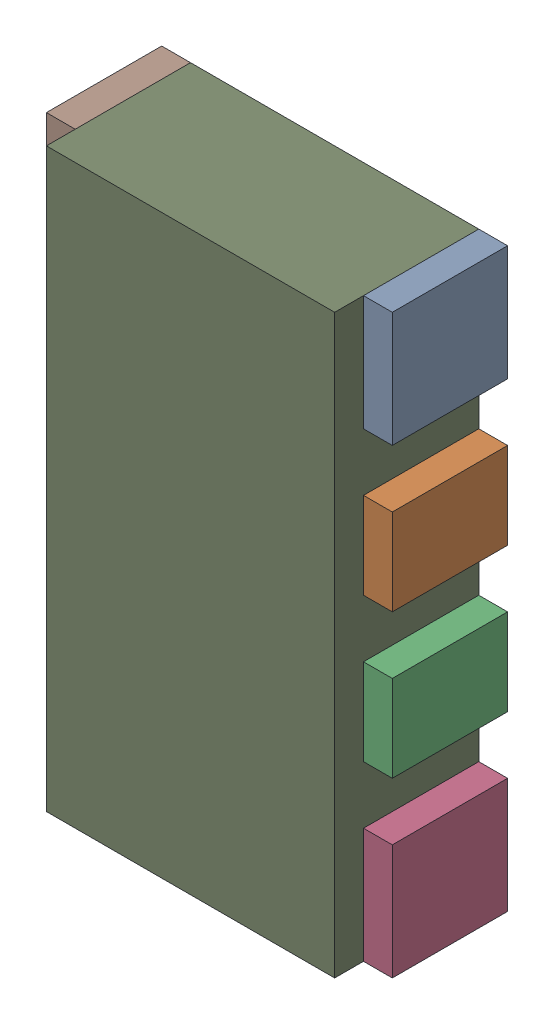
SolidWorks assembly RN4, configuration Default. Lengths in mm.
Overall size (1.2 2 0.5).
18 component instances, 3 part files, 0 mates.
Components (placement in the parent):
- 791587232-1: 791587232 [Default] at (128.9 27.15 0) size (0.1 0.4 0.4)
  - Extruded_10-1: Extruded_10 [Default] at origin size (0.1 0.4 0.4)
- 836750576-1: 836750576 [Default] at (128.9 26.6 0) size (0.1 0.3 0.4)
  - Extruded_14-1: Extruded_14 [Default] at origin size (0.1 0.3 0.4)
- 836750576-2: 836750576 [Default] at (128.9 26.1 0) size (0.1 0.3 0.4)
  - Extruded_14-1: Extruded_14 [Default] at origin size (0.1 0.3 0.4)
- 791587232-2: 791587232 [Default] at (128.9 25.55 0) size (0.1 0.4 0.4)
  - Extruded_10-1: Extruded_10 [Default] at origin size (0.1 0.4 0.4)
- 791587232-3: 791587232 [Default] at (127.8 25.55 0) size (0.1 0.4 0.4)
  - Extruded_10-1: Extruded_10 [Default] at origin size (0.1 0.4 0.4)
- 836750576-3: 836750576 [Default] at (127.8 26.1 0) size (0.1 0.3 0.4)
  - Extruded_14-1: Extruded_14 [Default] at origin size (0.1 0.3 0.4)
- 836750576-4: 836750576 [Default] at (127.8 26.6 0) size (0.1 0.3 0.4)
  - Extruded_14-1: Extruded_14 [Default] at origin size (0.1 0.3 0.4)
- 791587232-4: 791587232 [Default] at (127.8 27.15 0) size (0.1 0.4 0.4)
  - Extruded_10-1: Extruded_10 [Default] at origin size (0.1 0.4 0.4)
- 836750320-1: 836750320 [Default] at (128.35 26.35 0) size (1 2 0.5)
  - Extruded_15-1: Extruded_15 [Default] at origin size (1 2 0.5)
